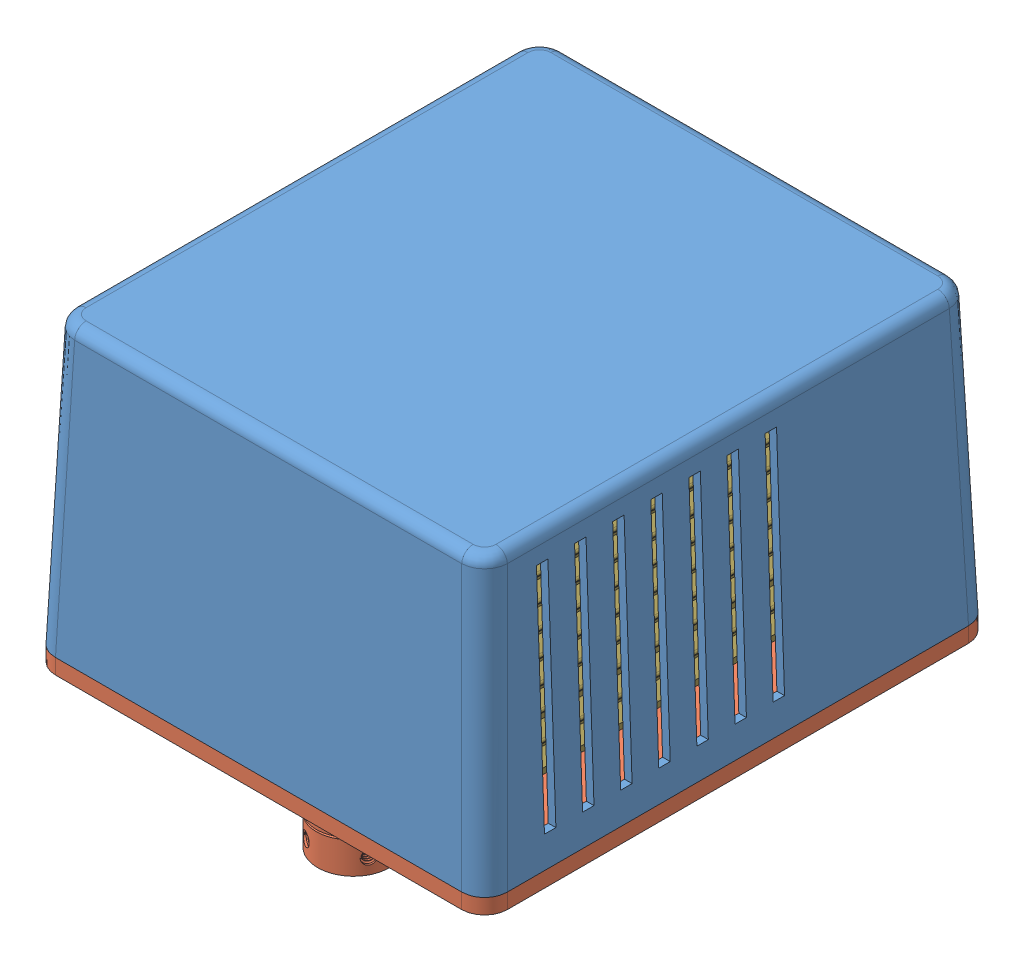
SolidWorks assembly Toptop, configuration Default. Lengths in mm.
Overall size (118.6 104 133).
221 component instances, 56 part files, 10 mates.
Components (placement in the parent):
- top-1: top [Default] at (57.778 57.3962 141.5728) size (118.6 75 133)
- Bottom-1: Bottom [Default] at origin size (118.6 4 133)
- NEMA17.step-1: NEMA17.step [Default] at (36.6836 96.8962 162.0519) x (1 0 0) z (0 0 -1) size (42 64.52 46)
- TB6600(AP203).step-1: TB6600(AP203).step [Default] at (19.7789 127.8941 142.9646) x (0 0 -1) z (1 0 0) size (97 69.65 28.45)
  - 0.step-1: 0.step [Default] at origin size (97 69.65 28.45)
    - 0-1.step-1: 0-1.step [Default] at origin size (74.62 23.17 13.05)
      - 0-0.step-1: 0-0.step [Default] at origin size (4.95 4.95 5.4)
      - 0-2.step-1: 0-2.step [Default] at origin size (4.95 4.95 5.4)
      - 0-3.step-1: 0-3.step [Default] at origin size (10.9 16 9)
    - 0-4.step-1: 0-4.step [Default] at origin size (76.72 49.67 0.1)
    - 0-5.step-1: 0-5.step [Default] at origin size (30 12 8.2)
    - 0-6.step-1: 0-6.step [Default] at origin size (30 12 8.2)
    - 0-7.step-1: 0-7.step [Default] at origin size (30 17 15)
    - 0-8.step-1: 0-8.step [Default] at origin size (30 17 15)
    - 0-9.step-1: 0-9.step [Default] at origin size (97 57 27.05)
    - 0-10.step-1: 0-10.step [Default] at origin size (82 54 20)
    - 0-11.step-1: 0-11.step [Default] at origin size (76 50 1.54)
- 3D map.step-1: 3D map.step [Default] at (119.3486 115.802 -14.1882) x (0 0 1) z (0 -1 0) size (66.42 42.04 16.02)
  - Board.step-1: Board.step [Default] at origin size (66.42 42.04 0.41)
    - Open CASCADE STEP translator 7.5 1.1.1.step-1: Open CASCADE STEP translator 7.5 1.1.1.step [Default] at (0 0 -0.4115) size (66.42 42.04 0.41)
  - J6.step-1: J6.step [Default] at origin size (7.4 5.75 10.4)
    - Conn_JST_B2B-XH-AM_LF_SN_eec.step-1: Conn_JST_B2B-XH-AM_LF_SN_eec.step [Default] at (102.235 74.803 0) size (7.4 5.75 10.4)
      - 1.step-1: 1.step [Default] x (1 0 0) z (0 -1 0) size (3.14 10.2 0.64)
      - 2.step-1: 2.step [Default] x (1 0 0) z (0 -1 0) size (7.4 8.5 5.75)
      - JST.step-1: JST.step [Default] at (3.6995 1.5028 6.0136) x (0 1 0) z (1 0 0) size (1.59 0.67 0.01)
      - Pin1_Triangle.step-1: Pin1_Triangle.step [Default] at (1.2756 -2.776 -2.2788) x (1 0 0) z (0 -1 0) size (0.78 0.53 0.01)
  - U1.step-1: U1.step [Default] at origin size (14 14 1.6)
    - 6089135632.step-1: 6089135632.step [Default] at (142.113 58.293 0) size (14 14 1.6)
      - Extruded.step-1: Extruded.step [Default] at origin size (14 14 1.6)
  - C15.step-1: C15.step [Default] at origin size (1.25 2.01 0.94)
    - 6091724976.step-1: 6091724976.step [Default] at (109.22 68.961 0) x (0 1 0) z (0 0 1) size (2.01 1.25 0.94)
      - Fillet1.step-1: Fillet1.step [Default] at origin size (0.5 1.25 0.94)
      - Fillet2.step-1: Fillet2.step [Default] at origin size (0.5 1.25 0.94)
      - body2.step-1: body2.step [Default] at origin size (1.01 1.22 0.92)
  - C14.step-1: C14.step [Default] at origin size (3.4 1.8 1.75)
    - 6091718736.step-1: 6091718736.step [Default] at (103.178 68.2435 0) x (1 0 0) z (0 -1 0) size (3.4 1.75 1.8)
  - C12.step-1: C12.step [Default] at origin size (1.25 2.01 0.94)
    - 6091725296.step-1: 6091725296.step [Default] at (153.543 57.785 0) x (0 -1 0) z (0 0 1) size (2.01 1.25 0.94)
      - Fillet1-0.step-1: Fillet1-0.step [Default] at origin size (0.5 1.25 0.94)
      - Fillet2-1.step-1: Fillet2-1.step [Default] at origin size (0.5 1.25 0.94)
      - body2-2.step-1: body2-2.step [Default] at origin size (1.01 1.22 0.92)
  - C6.step-1: C6.step [Default] at origin size (1.25 2.01 0.94)
    - 6091724976.step-1: 6091724976.step [Default] at (153.543 62.055 0) x (0 1 0) z (0 0 1) size (2.01 1.25 0.94)
      - Fillet1.step-1: Fillet1.step [Default] at origin size (0.5 1.25 0.94)
      - Fillet2.step-1: Fillet2.step [Default] at origin size (0.5 1.25 0.94)
      - body2.step-1: body2.step [Default] at origin size (1.01 1.22 0.92)
  - C5.step-1: C5.step [Default] at origin size (1.25 2.01 0.94)
    - 6091724976.step-1: 6091724976.step [Default] at (127.127 56.769 0) x (0 1 0) z (0 0 1) size (2.01 1.25 0.94)
      - Fillet1.step-1: Fillet1.step [Default] at origin size (0.5 1.25 0.94)
      - Fillet2.step-1: Fillet2.step [Default] at origin size (0.5 1.25 0.94)
      - body2.step-1: body2.step [Default] at origin size (1.01 1.22 0.92)
  - C13.step-1: C13.step [Default] at origin size (2 1.25 0.9)
    - 6091720736.step-1: 6091720736.step [Default] at (159.337 49.911 0) x (-1 0 0) z (0 0 1) size (2 1.25 0.9)
      - Fillet1-3.step-1: Fillet1-3.step [Default] at origin size (0.5 1.25 0.9)
      - Fillet2-4.step-1: Fillet2-4.step [Default] at origin size (0.5 1.25 0.9)
      - body2-5.step-1: body2-5.step [Default] at origin size (1 1.22 0.88)
  - C11.step-1: C11.step [Default] at origin size (1.25 2 0.9)
    - 6091721776.step-1: 6091721776.step [Default] at (153.67 50.038 0) x (0 1 0) z (0 0 1) size (2 1.25 0.9)
      - Fillet1-6.step-1: Fillet1-6.step [Default] at origin size (0.5 1.25 0.9)
      - Fillet2-7.step-1: Fillet2-7.step [Default] at origin size (0.5 1.25 0.9)
      - body2-8.step-1: body2-8.step [Default] at origin size (1 1.22 0.88)
  - C10.step-1: C10.step [Default] at origin size (1.25 2 0.9)
    - 6091721776.step-1: 6091721776.step [Default] at (153.67 53.975 0) x (0 1 0) z (0 0 1) size (2 1.25 0.9)
      - Fillet1-6.step-1: Fillet1-6.step [Default] at origin size (0.5 1.25 0.9)
      - Fillet2-7.step-1: Fillet2-7.step [Default] at origin size (0.5 1.25 0.9)
      - body2-8.step-1: body2-8.step [Default] at origin size (1 1.22 0.88)
  - C9.step-1: C9.step [Default] at origin size (1.25 2 0.9)
    - 6091721776.step-1: 6091721776.step [Default] at (153.416 66.294 0) x (0 1 0) z (0 0 1) size (2 1.25 0.9)
      - Fillet1-6.step-1: Fillet1-6.step [Default] at origin size (0.5 1.25 0.9)
      - Fillet2-7.step-1: Fillet2-7.step [Default] at origin size (0.5 1.25 0.9)
      - body2-8.step-1: body2-8.step [Default] at origin size (1 1.22 0.88)
  - C8.step-1: C8.step [Default] at origin size (1.25 2 0.9)
    - 6091721776.step-1: 6091721776.step [Default] at (126.873 61.468 0) x (0 1 0) z (0 0 1) size (2 1.25 0.9)
      - Fillet1-6.step-1: Fillet1-6.step [Default] at origin size (0.5 1.25 0.9)
      - Fillet2-7.step-1: Fillet2-7.step [Default] at origin size (0.5 1.25 0.9)
      - body2-8.step-1: body2-8.step [Default] at origin size (1 1.22 0.88)
  - C7.step-1: C7.step [Default] at origin size (1.25 2 0.9)
    - 6091721776.step-1: 6091721776.step [Default] at (129.794 61.293 0) x (0 1 0) z (0 0 1) size (2 1.25 0.9)
      - Fillet1-6.step-1: Fillet1-6.step [Default] at origin size (0.5 1.25 0.9)
      - Fillet2-7.step-1: Fillet2-7.step [Default] at origin size (0.5 1.25 0.9)
      - body2-8.step-1: body2-8.step [Default] at origin size (1 1.22 0.88)
  - C4.step-1: C4.step [Default] at origin size (2 1.25 0.9)
    - 6091720736.step-1: 6091720736.step [Default] at (126.492 76.073 0) x (-1 0 0) z (0 0 1) size (2 1.25 0.9)
      - Fillet1-3.step-1: Fillet1-3.step [Default] at origin size (0.5 1.25 0.9)
      - Fillet2-4.step-1: Fillet2-4.step [Default] at origin size (0.5 1.25 0.9)
      - body2-5.step-1: body2-5.step [Default] at origin size (1 1.22 0.88)
  - C3.step-1: C3.step [Default] at origin size (1.25 2 0.9)
    - 6091721776.step-1: 6091721776.step [Default] at (129.794 56.896 0) x (0 1 0) z (0 0 1) size (2 1.25 0.9)
      - Fillet1-6.step-1: Fillet1-6.step [Default] at origin size (0.5 1.25 0.9)
      - Fillet2-7.step-1: Fillet2-7.step [Default] at origin size (0.5 1.25 0.9)
      - body2-8.step-1: body2-8.step [Default] at origin size (1 1.22 0.88)
  - C2.step-1: C2.step [Default] at origin size (2 1.25 0.9)
    - 6091720736.step-1: 6091720736.step [Default] at (121.158 44.323 0) x (-1 0 0) z (0 0 1) size (2 1.25 0.9)
      - Fillet1-3.step-1: Fillet1-3.step [Default] at origin size (0.5 1.25 0.9)
      - Fillet2-4.step-1: Fillet2-4.step [Default] at origin size (0.5 1.25 0.9)
      - body2-5.step-1: body2-5.step [Default] at origin size (1 1.22 0.88)
  - C1.step-1: C1.step [Default] at origin size (2 1.25 0.9)
    - 6091720736.step-1: 6091720736.step [Default] at (126.032 44.323 0) x (-1 0 0) z (0 0 1) size (2 1.25 0.9)
      - Fillet1-3.step-1: Fillet1-3.step [Default] at origin size (0.5 1.25 0.9)
      - Fillet2-4.step-1: Fillet2-4.step [Default] at origin size (0.5 1.25 0.9)
      - body2-5.step-1: body2-5.step [Default] at origin size (1 1.22 0.88)
  - Y1.step-1: Y1.step [Default] at origin size (4.9 13.4 4.3)
    - 6091718096.step-1: 6091718096.step [Default] at (159.639 60.503 0) x (0 1 0) z (0 0 1) size (13.4 4.9 4.3)
  - U2.step-1: U2.step [Default] at origin size (10 6 1.8)
    - 6091724256.step-1: 6091724256.step [Default] at (121.92 50.629 0) x (0 -1 0) z (-1 0 0) size (6 1.8 10)
  - S1.step-1: S1.step [Default] at origin size (7.68 6.01 7.8)
    - 6091725456.step-1: 6091725456.step [Default] at (152.654 44.704 3.32) x (0 1 0) z (1 0 0) size (6.01 7.8 7.68)
  - R8.step-1: R8.step [Default] at origin size (2 1.25 0.6)
    - 6091722896.step-1: 6091722896.step [Default] at (159.639 46.99 0) x (-1 0 0) z (0 0 1) size (2 1.25 0.6)
      - term1.step-1: term1.step [Default] at (-1 -0.625 0) size (0.4 1.25 0.6)
      - term2.step-1: term2.step [Default] at (0.6 -0.625 0) size (0.4 1.25 0.6)
      - body.step-1: body.step [Default] at (-0.6 -0.6125 0.006) size (1.2 1.22 0.59)
  - R5.step-1: R5.step [Default] at origin size (2 1.25 0.6)
    - 6091723056.step-1: 6091723056.step [Default] at (115.062 72.136 0) size (2 1.25 0.6)
      - term1-9.step-1: term1-9.step [Default] at (-1 -0.625 0) size (0.4 1.25 0.6)
      - term2-10.step-1: term2-10.step [Default] at (0.6 -0.625 0) size (0.4 1.25 0.6)
      - body-11.step-1: body-11.step [Default] at (-0.6 -0.6125 0.006) size (1.2 1.22 0.59)
  - R4.step-1: R4.step [Default] at origin size (2 1.25 0.5)
    - 6091727136.step-1: 6091727136.step [Default] at (132.08 76.2 0) size (2 1.25 0.5)
      - solidBody.step-1: solidBody.step [Default] at origin size (1.96 1.25 0.46)
      - solidTop.step-1: solidTop.step [Default] at origin size (1.2 1.15 0.02)
      - solidTerminal1.step-1: solidTerminal1.step [Default] at origin size (2 1.25 0.02)
      - solidTerminal2.step-1: solidTerminal2.step [Default] at origin size (2 1.25 0.02)
      - solidTerminal3.step-1: solidTerminal3.step [Default] at origin size (2 1.25 0.5)
  - R3.step-1: R3.step [Default] at origin size (2 1.25 0.5)
    - 6091727136.step-1: 6091727136.step [Default] at (114.681 68.58 0) size (2 1.25 0.5)
      - solidBody.step-1: solidBody.step [Default] at origin size (1.96 1.25 0.46)
      - solidTop.step-1: solidTop.step [Default] at origin size (1.2 1.15 0.02)
      - solidTerminal1.step-1: solidTerminal1.step [Default] at origin size (2 1.25 0.02)
      - solidTerminal2.step-1: solidTerminal2.step [Default] at origin size (2 1.25 0.02)
      - solidTerminal3.step-1: solidTerminal3.step [Default] at origin size (2 1.25 0.5)
  - R2.step-1: R2.step [Default] at origin size (2 1.25 0.5)
    - 6091727136.step-1: 6091727136.step [Default] at (114.554 75.565 0) size (2 1.25 0.5)
      - solidBody.step-1: solidBody.step [Default] at origin size (1.96 1.25 0.46)
      - solidTop.step-1: solidTop.step [Default] at origin size (1.2 1.15 0.02)
      - solidTerminal1.step-1: solidTerminal1.step [Default] at origin size (2 1.25 0.02)
      - solidTerminal2.step-1: solidTerminal2.step [Default] at origin size (2 1.25 0.02)
      - solidTerminal3.step-1: solidTerminal3.step [Default] at origin size (2 1.25 0.5)
  - R1.step-1: R1.step [Default] at origin size (2 1.25 0.5)
    - 6091727136.step-1: 6091727136.step [Default] at (121.158 75.946 0) size (2 1.25 0.5)
      - solidBody.step-1: solidBody.step [Default] at origin size (1.96 1.25 0.46)
      - solidTop.step-1: solidTop.step [Default] at origin size (1.2 1.15 0.02)
      - solidTerminal1.step-1: solidTerminal1.step [Default] at origin size (2 1.25 0.02)
      - solidTerminal2.step-1: solidTerminal2.step [Default] at origin size (2 1.25 0.02)
      - solidTerminal3.step-1: solidTerminal3.step [Default] at origin size (2 1.25 0.5)
  - R6.step-1: R6.step [Default] at origin size (2 1.25 0.5)
    - 6091727136.step-1: 6091727136.step [Default] at (132.654 71.755 0) size (2 1.25 0.5)
      - solidBody.step-1: solidBody.step [Default] at origin size (1.96 1.25 0.46)
      - solidTop.step-1: solidTop.step [Default] at origin size (1.2 1.15 0.02)
      - solidTerminal1.step-1: solidTerminal1.step [Default] at origin size (2 1.25 0.02)
      - solidTerminal2.step-1: solidTerminal2.step [Default] at origin size (2 1.25 0.02)
      - solidTerminal3.step-1: solidTerminal3.step [Default] at origin size (2 1.25 0.5)
  - R7.step-1: R7.step [Default] at origin size (2 1.25 0.5)
    - 6091727136.step-1: 6091727136.step [Default] at (129.86 67.056 0) size (2 1.25 0.5)
      - solidBody.step-1: solidBody.step [Default] at origin size (1.96 1.25 0.46)
      - solidTop.step-1: solidTop.step [Default] at origin size (1.2 1.15 0.02)
      - solidTerminal1.step-1: solidTerminal1.step [Default] at origin size (2 1.25 0.02)
      - solidTerminal2.step-1: solidTerminal2.step [Default] at origin size (2 1.25 0.02)
      - solidTerminal3.step-1: solidTerminal3.step [Default] at origin size (2 1.25 0.5)
  - PS1.step-1: PS1.step [Default] at origin size (4.5 2.6 4.51)
    - 6091719936.step-1: 6091719936.step [Default] at (119.38 60.325 0) x (-1 0 0) z (0 0 1) size (4.5 2.6 4.51)
  - U4.step-1: U4.step [Default] at origin size (5.99 1.68 5.69)
    - 6091724176.step-1: 6091724176.step [Default] at (106.172 45.72 0) x (1 0 0) z (0 0 1) size (5.99 1.68 5.69)
      - body.step-1: body.step [Default] at (0 0 0.1) size (1.2 1.22 0.59)
      - Leads.step-1: Leads.step [Default] at origin size (5.99 0.91 5.1)
  - J7.step-1: J7.step [Default] at origin size (14.5 9.5 14.5)
    - 6091729056.step-1: 6091729056.step [Default] at (101.605 60.533 5.67) x (0 -1 0) z (0 0 1) size (9.5 14.5 14.5)
  - J5.step-1: J5.step [Default] at origin size (22.4 5.75 10.4)
    - 6091719056.step-1: 6091719056.step [Default] at (149.793 72.5 0) x (-1 0 0) z (0 1 0) size (22.4 10.4 5.75)
      - BxB-XH-A_08.step-1: BxB-XH-A_08.step [Default] at (8.75 0 0.525) x (-1 0 0) z (0 0 -1) size (22.4 10.4 5.75)
  - J4.step-1: J4.step [Default] at origin size (12.5 3.8 9.2)
    - 6091716576.step-1: 6091716576.step [Default] at (127.7687 80.264 0) x (-1 0 0) z (0 1 0) size (12.5 9.2 3.8)
  - J3.step-1: J3.step [Default] at origin size (17.4 5.75 10.4)
    - 6091725216.step-1: 6091725216.step [Default] at (138.149 44.687 0) x (-1 0 0) z (0 1 0) size (17.4 10.4 5.75)
  - J2.step-1: J2.step [Default] at origin size (12.5 3.8 9.2)
    - 6091716576.step-1: 6091716576.step [Default] at (113.859 80.264 0) x (-1 0 0) z (0 1 0) size (12.5 9.2 3.8)
  - J1.step-1: J1.step [Default] at origin size (22.4 5.75 10.4)
    - 6091719056.step-1: 6091719056.step [Default] at (147.046 79.485 0) x (-1 0 0) z (0 1 0) size (22.4 10.4 5.75)
      - BxB-XH-A_08.step-1: BxB-XH-A_08.step [Default] at (8.75 0 0.525) x (-1 0 0) z (0 0 -1) size (22.4 10.4 5.75)
  - U3.step-1: U3.step [Default] at origin size (6.4 7.8 1.13)
    - 6091715616.step-1: 6091715616.step [Default] at (122.665 69.383 0) size (6.4 7.8 1.13)
      - BODY-TSSOP.step-1: BODY-TSSOP.step [Default] at (0 0 0.68) x (1 0 0) z (0 -1 0) size (4.4 1 7.8)
      - LEAD-TSSOP.step-1: LEAD-TSSOP.step [Default] at (-2.575 3.575 0.25) x (0 -1 0) z (-1 0 0) size (0.24 0.68 1)
      - LEAD-TSSOP.step-2: LEAD-TSSOP.step [Default] at (-2.575 2.925 0.25) x (0 -1 0) z (-1 0 0) size (0.24 0.68 1)
      - LEAD-TSSOP.step-3: LEAD-TSSOP.step [Default] at (-2.575 2.275 0.25) x (0 -1 0) z (-1 0 0) size (0.24 0.68 1)
      - LEAD-TSSOP.step-4: LEAD-TSSOP.step [Default] at (-2.575 1.625 0.25) x (0 -1 0) z (-1 0 0) size (0.24 0.68 1)
      - LEAD-TSSOP.step-5: LEAD-TSSOP.step [Default] at (-2.575 0.975 0.25) x (0 -1 0) z (-1 0 0) size (0.24 0.68 1)
      - LEAD-TSSOP.step-6: LEAD-TSSOP.step [Default] at (-2.575 0.325 0.25) x (0 -1 0) z (-1 0 0) size (0.24 0.68 1)
      - LEAD-TSSOP.step-7: LEAD-TSSOP.step [Default] at (-2.575 -0.325 0.25) x (0 -1 0) z (-1 0 0) size (0.24 0.68 1)
      - LEAD-TSSOP.step-8: LEAD-TSSOP.step [Default] at (-2.575 -0.975 0.25) x (0 -1 0) z (-1 0 0) size (0.24 0.68 1)
      - LEAD-TSSOP.step-9: LEAD-TSSOP.step [Default] at (-2.575 -1.625 0.25) x (0 -1 0) z (-1 0 0) size (0.24 0.68 1)
      - LEAD-TSSOP.step-10: LEAD-TSSOP.step [Default] at (-2.575 -2.275 0.25) x (0 -1 0) z (-1 0 0) size (0.24 0.68 1)
      - LEAD-TSSOP.step-11: LEAD-TSSOP.step [Default] at (-2.575 -2.925 0.25) x (0 -1 0) z (-1 0 0) size (0.24 0.68 1)
      - LEAD-TSSOP.step-12: LEAD-TSSOP.step [Default] at (-2.575 -3.575 0.25) x (0 -1 0) z (-1 0 0) size (0.24 0.68 1)
      - LEAD-TSSOP.step-13: LEAD-TSSOP.step [Default] at (2.575 -3.575 0.25) x (0 1 0) z (1 0 0) size (0.24 0.68 1)
      - LEAD-TSSOP.step-14: LEAD-TSSOP.step [Default] at (2.575 -2.925 0.25) x (0 1 0) z (1 0 0) size (0.24 0.68 1)
      - LEAD-TSSOP.step-15: LEAD-TSSOP.step [Default] at (2.575 -2.275 0.25) x (0 1 0) z (1 0 0) size (0.24 0.68 1)
      - LEAD-TSSOP.step-16: LEAD-TSSOP.step [Default] at (2.575 -1.625 0.25) x (0 1 0) z (1 0 0) size (0.24 0.68 1)
      - LEAD-TSSOP.step-17: LEAD-TSSOP.step [Default] at (2.575 -0.975 0.25) x (0 1 0) z (1 0 0) size (0.24 0.68 1)
      - LEAD-TSSOP.step-18: LEAD-TSSOP.step [Default] at (2.575 -0.325 0.25) x (0 1 0) z (1 0 0) size (0.24 0.68 1)
      - LEAD-TSSOP.step-19: LEAD-TSSOP.step [Default] at (2.575 0.325 0.25) x (0 1 0) z (1 0 0) size (0.24 0.68 1)
      - LEAD-TSSOP.step-20: LEAD-TSSOP.step [Default] at (2.575 0.975 0.25) x (0 1 0) z (1 0 0) size (0.24 0.68 1)
      - LEAD-TSSOP.step-21: LEAD-TSSOP.step [Default] at (2.575 1.625 0.25) x (0 1 0) z (1 0 0) size (0.24 0.68 1)
      - LEAD-TSSOP.step-22: LEAD-TSSOP.step [Default] at (2.575 2.275 0.25) x (0 1 0) z (1 0 0) size (0.24 0.68 1)
      - LEAD-TSSOP.step-23: LEAD-TSSOP.step [Default] at (2.575 2.925 0.25) x (0 1 0) z (1 0 0) size (0.24 0.68 1)
      - LEAD-TSSOP.step-24: LEAD-TSSOP.step [Default] at (2.575 3.575 0.25) x (0 1 0) z (1 0 0) size (0.24 0.68 1)
- TB6600(AP203) (1).step-1: TB6600(AP203) (1).step [Default] at (95.7624 127.8941 142.7076) x (0 0 1) z (-1 0 0) size (97 69.65 28.45)
  - 0.step-1: 0.step [Default] at origin size (97 69.65 28.45)
    - 0-1.step-1: 0-1.step [Default] at origin size (74.62 23.17 13.05)
      - 0-0.step-1: 0-0.step [Default] at origin size (4.95 4.95 5.4)
      - 0-2.step-1: 0-2.step [Default] at origin size (4.95 4.95 5.4)
      - 0-3.step-1: 0-3.step [Default] at origin size (10.9 16 9)
    - 0-4.step-1: 0-4.step [Default] at origin size (76.72 49.67 0.1)
    - 0-5.step-1: 0-5.step [Default] at origin size (30 12 8.2)
    - 0-6.step-1: 0-6.step [Default] at origin size (30 12 8.2)
    - 0-7.step-1: 0-7.step [Default] at origin size (30 17 15)
    - 0-8.step-1: 0-8.step [Default] at origin size (30 17 15)
    - 0-9.step-1: 0-9.step [Default] at origin size (97 57 27.05)
    - 0-10.step-1: 0-10.step [Default] at origin size (82 54 20)
    - 0-11.step-1: 0-11.step [Default] at origin size (76 50 1.54)
- acoplamiento motor-1: acoplamiento motor [Predeterminado] at (57.6836 40.8962 183.0519) x (0.450916 0 -0.892566) z (0.892566 0 0.450916) size (19.29 25 19.77)
Mates (geometry in assembly coordinates):
- Parallel2: parallel anti-aligned: plane of top-1 through (36.4768 132.3972 162.0715) normal (1 0 0); plane of NEMA17.step-1 through (36.6836 87.3962 196.6165) normal (-1 0 0)
- Coincident4: coincident anti-aligned: plane of top-1 through (57.778 130.3962 141.5728) normal (0 -1 0); plane of TB6600(AP203).step-1/0.step-1/0-9.step-1 through (11.8768 130.3962 142.9646) normal (0 1 0)
- Parallel3: parallel aligned: line of top-1 through (0.4792 57.3962 81.0715) axis (0 0 1); line of TB6600(AP203).step-1/0.step-1/0-9.step-1 through (4.4768 73.3962 94.4646) axis (0 0 1)
- Lock2: lock: unknown of top-1; unknown of NEMA17.step-1
- Parallel4: parallel anti-aligned: plane of top-1 through (57.778 130.3962 141.5728) normal (0 -1 0); plane of 3D map.step-1/Board.step-1/Open CASCADE STEP translator 7.5 1.1.1.step-1 through (57.0551 116.2135 116.1773) normal (0 1 0)
- Parallel5: parallel anti-aligned: line of top-1 through (0.4792 57.3962 81.0715) axis (0 0 1); line of 3D map.step-1/Board.step-1/Open CASCADE STEP translator 7.5 1.1.1.step-1 through (36.0366 115.802 149.3878) axis (0 0 -1)
- Coincident10: coincident anti-aligned: plane of top-1 through (57.778 130.3962 141.5728) normal (0 -1 0); plane of TB6600(AP203) (1).step-1/0.step-1/0-9.step-1 through (103.6645 130.3962 142.7076) normal (0 1 0)
- Parallel6: parallel aligned: line of top-1 through (117.078 57.3962 202.0764) axis (0 0 -1); line of TB6600(AP203) (1).step-1/0.step-1/0-9.step-1 through (111.0645 73.3962 191.2076) axis (0 0 -1)
- Concentric2: concentric aligned: circle of NEMA17.step-1; circle of acoplamiento motor-1
- Coincident13: coincident anti-aligned: plane of Bottom-1 through (111.0743 53.3962 202.0691) normal (0 -1 0); plane of acoplamiento motor-1 through (57.6836 53.3962 183.0519) normal (0 1 0)
